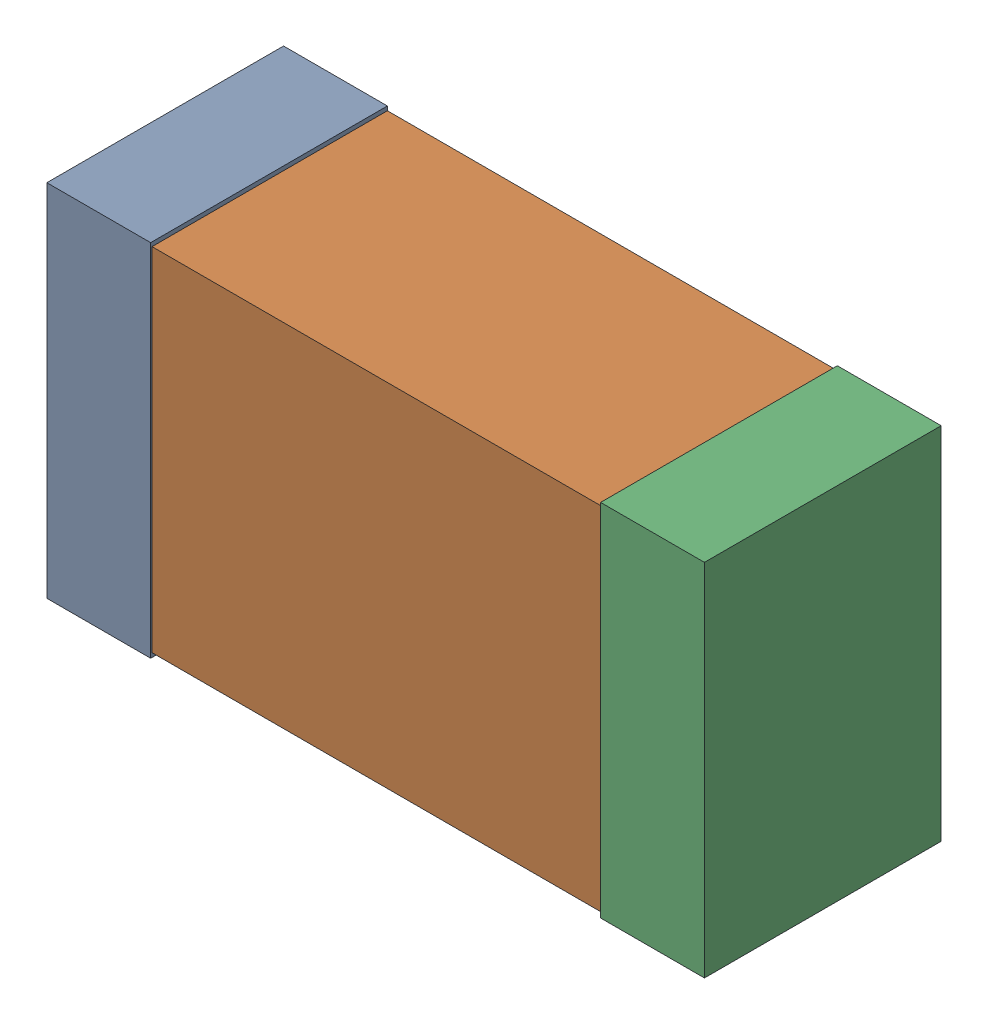
SolidWorks assembly C13_Motor_5Kanaloa_v2.0.0_Motor, configuration Default. Lengths in mm.
Overall size (2.38 1.3 0.85).
6 component instances, 2 part files, 0 mates.
Components (placement in the parent):
- 352877648-1: 352877648 [Default] at (144.991 87.63 0) size (0.38 1.3 0.85)
  - Extruded_14-1: Extruded_14 [Default] at origin size (0.38 1.3 0.85)
- 352877392-1: 352877392 [Default] at (145.991 87.63 0) size (2.2 1.27 0.85)
  - Extruded_15-1: Extruded_15 [Default] at origin size (2.2 1.27 0.85)
- 352877648-2: 352877648 [Default] at (146.991 87.63 0) size (0.38 1.3 0.85)
  - Extruded_14-1: Extruded_14 [Default] at origin size (0.38 1.3 0.85)
